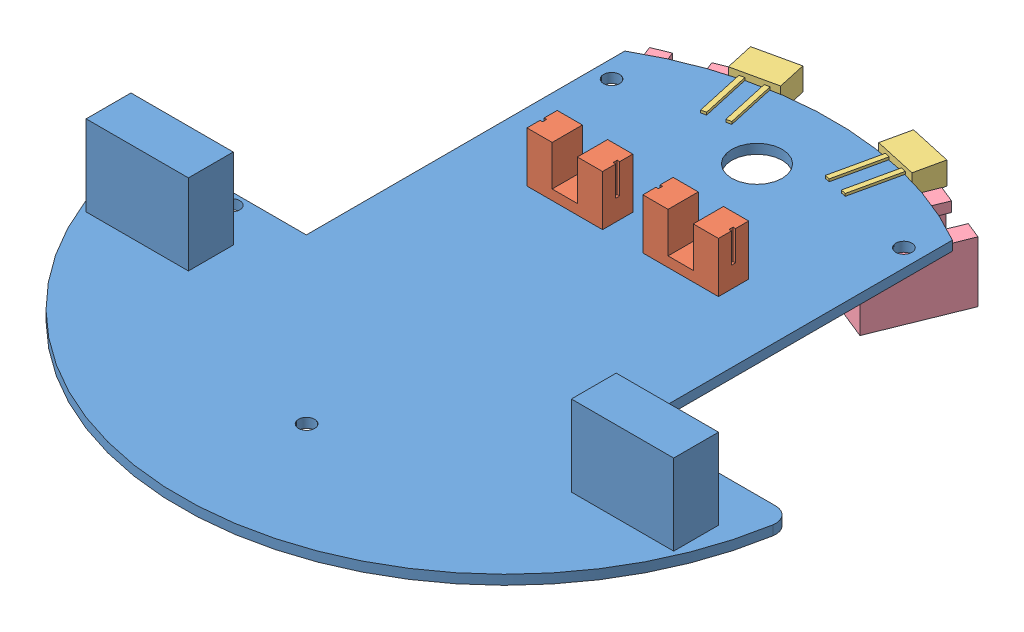
SolidWorks assembly MainPCB+Codeuse, configuration Default. Lengths in mm.
Overall size (127.34 29.9 134.46).
7 component instances, 4 part files, 17 mates.
Components (placement in the parent):
- MainPCB-CodeusePart-1: MainPCB-CodeusePart [Default] at (2.2604 0.7572 -2.3526) size (127.34 17.9 129.38)
- ITR9608-1: ITR9608 [Default] at (-9.2396 9.4572 -5.363) x (0 0 1) z (-1 0 0) size (6 12.5 15)
- ITR9608-2: ITR9608 [Default] at (13.7604 9.4572 0.637) x (0 0 -1) z (1 0 0) size (6 12.5 15)
- RPR 359F-6: RPR 359F [Default] at (17.4876 1.7072 -45.1534) x (-0.21644 0 0.976296) z (0 -1 0) size (15.8 8.7 4.5)
- RPR 359F-7: RPR 359F [Default] at (-12.9668 1.7072 -45.1534) x (0.21644 0 0.976296) z (0 1 0) size (15.8 8.7 4.5)
- RJ45Fem-1: RJ45Fem [Défaut] at (25.4397 0.7572 -31.3825) x (0.927184 0 0.374607) z (0 -1 0) size (13 18 12)
- RJ45Fem-4: RJ45Fem [Défaut] at (-20.9044 0.7572 -31.3275) x (0.927184 0 -0.374607) z (0 -1 0) size (13 18 12)
Mates (geometry in assembly coordinates):
- Coincident1: coincident aligned: plane of ITR9608-1 through (-1.7396 2.6572 0.637) normal (0 -1 0); plane of ITR9608-2 through (6.2604 2.6572 -5.363) normal (0 -1 0)
- Parallel2: parallel anti-aligned: plane of ITR9608-1 through (-16.7396 2.6572 0.637) normal (-1 0 0); plane of ITR9608-2 through (21.2604 2.6572 -5.363) normal (1 0 0)
- Coincident5: coincident aligned: plane of ITR9608-1 through (-9.2396 9.4572 0.637) normal (0 0 1); plane of ITR9608-2 through (13.7604 9.4572 0.637) normal (0 0 1)
- Distance1: distance = 8 mm anti-aligned: plane of ITR9608-1 through (-1.7396 2.6572 0.637) normal (1 0 0); plane of ITR9608-2 through (6.2604 2.6572 -5.363) normal (-1 0 0)
- Coincident10: coincident anti-aligned: plane of MainPCB-CodeusePart-1 through (2.2604 2.6572 -2.3526) normal (0 1 0); plane of ITR9608-1 through (-1.7396 2.6572 0.637) normal (0 -1 0)
- Distance2: distance = 13.5 mm aligned: plane of ITR9608-1 through (-16.7396 2.6572 0.637) normal (-1 0 0); plane of MainPCB-CodeusePart-1 through (-30.2396 2.6572 -29.0778) normal (-1 0 0)
- Distance3: distance = 36.2852 mm aligned: plane of ITR9608-2 through (13.7604 9.4572 -5.363) normal (0 0 -1); plane of MainPCB-CodeusePart-1 through (34.7604 2.6572 30.9222) normal (0 0 -1)
- Coincident27: coincident anti-aligned: plane of MainPCB-CodeusePart-1 through (2.2604 0.7572 -2.3526) normal (0 -1 0); plane of RPR 359F-6 through (16.6062 0.7572 -29.1651) normal (0 1 0)
- Tangent4: tangent anti-aligned: cylinder of MainPCB-CodeusePart-1 through (2.2604 2.6572 23.866) axis (0 -1 0) radius 64.8791; plane of RPR 359F-6 through (16.2322 1.7072 -39.4908) normal (-0.21644 0 0.976296)
- Coïncidente1: coincident anti-aligned: plane of MainPCB-CodeusePart-1 through (2.2604 0.7572 -2.3526) normal (0 -1 0); plane of RJ45Fem-1 through (25.4397 0.7572 -31.3825) normal (0 1 0)
- Angle1: planar angle = 5.899213 rad aligned: plane of RJ45Fem-1 through (24.3159 0.7572 -28.6009) normal (0.374607 0 -0.927184); plane of MainPCB-CodeusePart-1 through (-30.2396 2.6572 30.9222) normal (0 0 -1)
- Distance5: distance = 13.6518 mm: line of RJ45Fem-1 through (16.0415 -11.2428 -25.4728) axis (0 1 0); cylinder of MainPCB-CodeusePart-1 through (2.2604 2.6572 23.866) axis (0 -1 0) radius 64.8791
- Distance6: distance = 6.6655 mm: line of RJ45Fem-1 through (28.0949 -11.2428 -20.6029) axis (0 1 0); plane of MainPCB-CodeusePart-1 through (34.7604 2.6572 -29.0778) normal (1 0 0)
- Coïncidente3: coincident anti-aligned: plane of MainPCB-CodeusePart-1 through (2.2604 0.7572 -2.3526) normal (0 -1 0); plane of RJ45Fem-4 through (-20.9044 0.7572 -31.3275) normal (0 1 0)
- Angle2: planar angle = 0.383972 rad aligned: plane of MainPCB-CodeusePart-1 through (-30.2396 2.6572 30.9222) normal (0 0 -1); plane of RJ45Fem-4 through (-19.7806 0.7572 -28.546) normal (-0.374607 0 -0.927184)
- Distance7: distance = 6.68 mm: line of RJ45Fem-4 through (-23.5596 -11.2428 -20.5479) axis (0 1 0); plane of MainPCB-CodeusePart-1 through (-30.2396 2.6572 -29.0778) normal (-1 0 0)
- Distance9: distance = 56.34 mm: line of RJ45Fem-4 through (-11.5062 -11.2428 -25.4178) axis (0 1 0); plane of MainPCB-CodeusePart-1 through (-30.2396 2.6572 30.9222) normal (0 0 -1)
